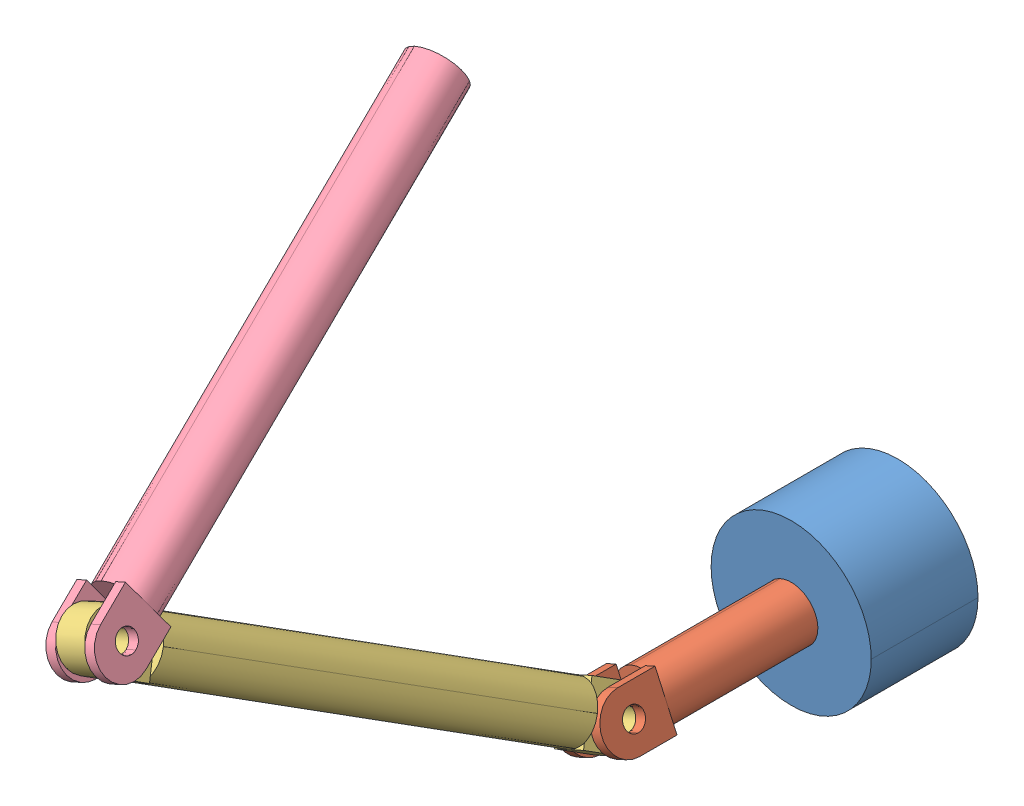
SolidWorks assembly articulated_manipulator_final, configuration Default. Lengths in mm.
Overall size (296.02 523.38 689.77).
4 component instances, 4 part files, 4 mates.
Components (placement in the parent):
- base_link-1: base_link [Default] at (9.6401 86.1631 184.2397) size (150 150 100)
- revolute_link_1-1: revolute_link_1 [Default] at (9.6401 86.1631 84.2397) x (0.41229 -0.911053 0) z (0 0 -1) size (50 50 300)
- revolute_link_2-1: revolute_link_2 [Default] at (-90.031 306.4105 759.6293) x (0.911053 0.41229 0) z (0.211168 -0.466626 -0.858876) size (50 50 500)
- revolute_link3-1: revolute_link3 [Default] at (-179.6392 504.4214 326.6523) x (-0.358717 0.792671 0.492945) z (0.203236 -0.449099 0.870061) size (50 50 500)
Mates (geometry in assembly coordinates):
- Concentric1: concentric anti-aligned: cylinder of base_link-1 through (9.6401 86.1631 184.2397) axis (0 0 1) radius 25; cylinder of revolute_link_1-1 through (9.6401 86.1631 84.2397) axis (0 0 -1) radius 25
- Coincident1: coincident aligned: plane of base_link-1 through (9.6401 86.1631 84.2397) normal (0 0 -1); plane of revolute_link_1-1 through (9.6401 86.1631 84.2397) normal (0 0 -1)
- Coincident5: coincident anti-aligned: circle of revolute_link_2-1; circle of revolute_link3-1
- Coincident6: coincident anti-aligned: circle of revolute_link_1-1; circle of revolute_link_2-1
